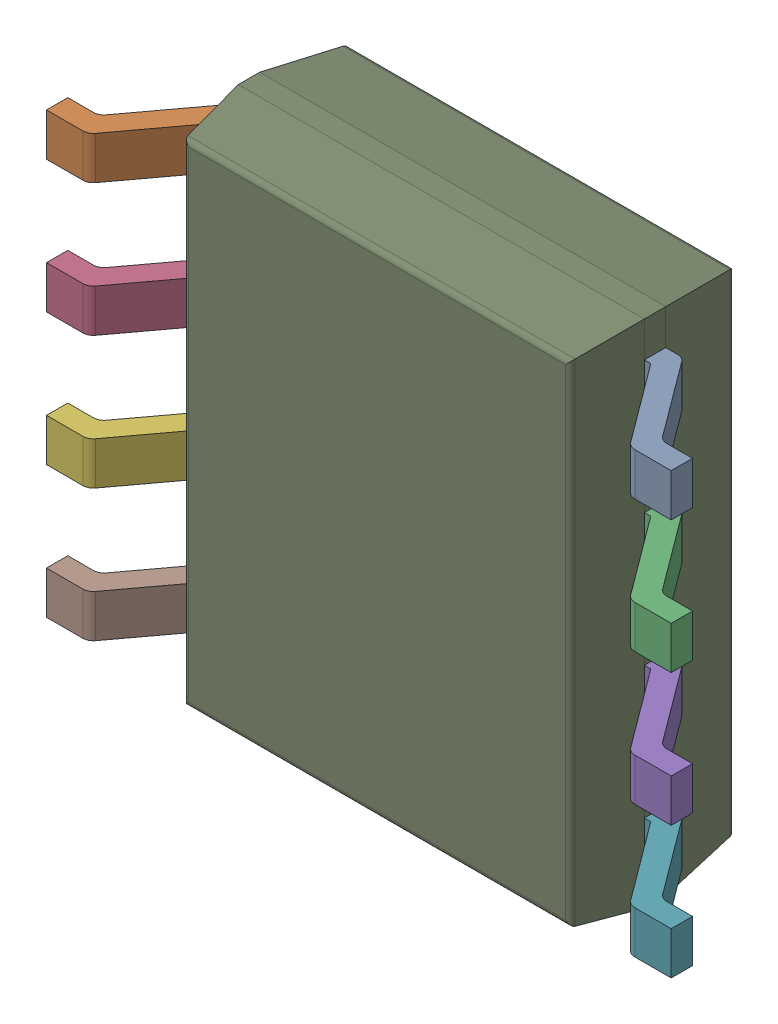
SolidWorks assembly IC1, configuration 默认. Lengths in mm.
Overall size (6 4.9 1.75).
11 component instances, 9 part files, 0 mates.
Components (placement in the parent):
- 6132017696-1: 6132017696 [默认] at (12.319 25.908 -1.6914) x (1 0 0) z (0 0 -1) size (6 4.9 1.75)
  - 6132017696-subassembly-1-1: 6132017696-subassembly-1 [默认] at origin size (6 4.22 1)
    - PinsArrayLR-1: PinsArrayLR [默认] at origin size (1.05 0.41 1)
    - PinsArrayLR-1-1: PinsArrayLR-1 [默认] at origin size (1.05 0.41 1)
    - PinsArrayLR-2-1: PinsArrayLR-2 [默认] at origin size (1.05 0.41 1)
    - PinsArrayLR-3-1: PinsArrayLR-3 [默认] at origin size (1.05 0.41 1)
    - PinsArrayLR-4-1: PinsArrayLR-4 [默认] at origin size (1.05 0.41 1)
    - PinsArrayLR-5-1: PinsArrayLR-5 [默认] at origin size (1.05 0.41 1)
    - PinsArrayLR-6-1: PinsArrayLR-6 [默认] at origin size (1.05 0.41 1)
    - PinsArrayLR-7-1: PinsArrayLR-7 [默认] at origin size (1.05 0.41 1)
  - Body-1: Body [默认] at origin size (3.9 4.9 1.57)
